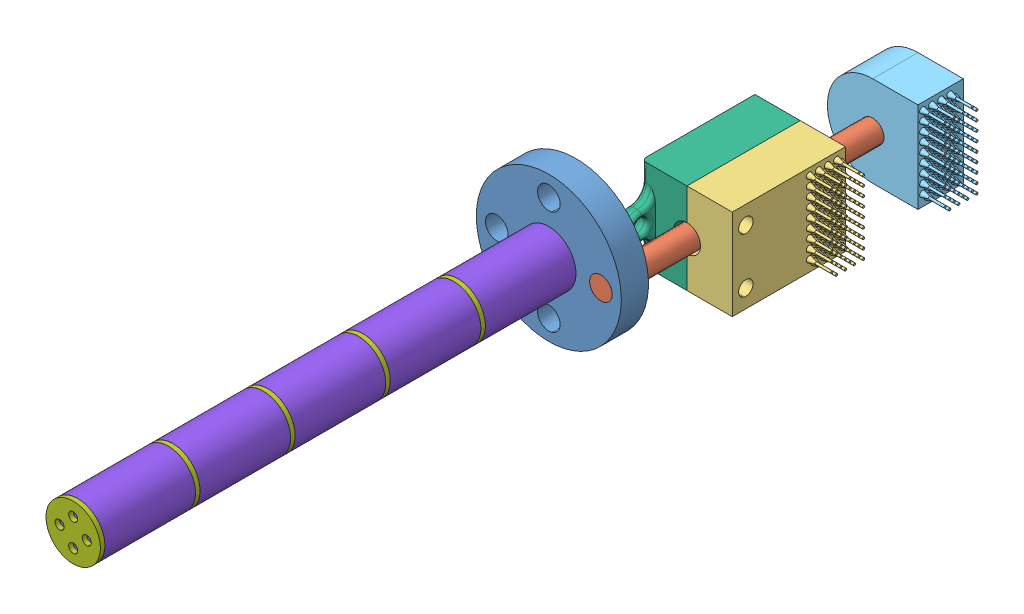
SolidWorks assembly snake, configuration ﾃﾞﾌｫﾙﾄ. Lengths in mm.
Overall size (48.52 35.13 175).
22 component instances, 8 part files, 14 mates.
Components (placement in the parent):
- plate_first-1: plate_first [ﾃﾞﾌｫﾙﾄ] at (-0.7263 1.8158 36) size (32 32 6)
- muscle_unit-1: muscle_unit [ﾃﾞﾌｫﾙﾄ] at (10.8937 1.4809 -53) x (-0.948329 -0.31729 0) z (0 0 1) size (30.19 26.94 70) (flexible)
  - axis-1: axis [ﾃﾞﾌｫﾙﾄ] at (0.0076 -0.3556 25) size (5 5 70)
  - kenzan_up-1: kenzan_up [ﾃﾞﾌｫﾙﾄ] at (0.0076 -0.3556 51) x (0.948329 -0.31729 0) z (0 0 1) size (15 20 25)
  - linear_bush-1: linear_bush [ﾃﾞﾌｫﾙﾄ] at (0.0076 -0.3556 53.25) x (0.529345 -0.848407 0) z (0 0 1) size (10 10 17)
  - kenzan_down-1: kenzan_down [ﾃﾞﾌｫﾙﾄ] at (0.0076 -0.3556 35) x (0.948329 -0.31729 0) z (0 0 -1) size (25 20 10)
  - kenzan_up_other-1: kenzan_up_other [ﾃﾞﾌｫﾙﾄ] at (0.0076 -0.3556 51) x (-0.948329 0.31729 0) z (0 0 1) size (10.14 20 31)
- snake_unit-1: snake_unit [ﾃﾞﾌｫﾙﾄ] at (3.1776 1.3921 42.5) size (12 12 21)
  - plate-1: plate [ﾃﾞﾌｫﾙﾄ] at (-3.9039 0.4237 19.5) size (12 12 1)
  - sponge-1: sponge [ﾃﾞﾌｫﾙﾄ] at (-3.9039 0.4237 -0.5) size (12 12 20)
- snake_unit-2: snake_unit [ﾃﾞﾌｫﾙﾄ] at (3.1776 1.3921 84.5) size (12 12 21)
  - plate-1: plate [ﾃﾞﾌｫﾙﾄ] at (-3.9039 0.4237 19.5) size (12 12 1)
  - sponge-1: sponge [ﾃﾞﾌｫﾙﾄ] at (-3.9039 0.4237 -0.5) size (12 12 20)
- snake_unit-3: snake_unit [ﾃﾞﾌｫﾙﾄ] at (-0.3026 5.7196 63.5) x (0 1 0) z (0 0 1) size (12 12 21)
  - plate-1: plate [ﾃﾞﾌｫﾙﾄ] at (-3.9039 0.4237 19.5) size (12 12 1)
  - sponge-1: sponge [ﾃﾞﾌｫﾙﾄ] at (-3.9039 0.4237 -0.5) size (12 12 20)
- snake_unit-4: snake_unit [ﾃﾞﾌｫﾙﾄ] at (3.1776 1.3921 105.5) size (12 12 21)
  - plate-1: plate [ﾃﾞﾌｫﾙﾄ] at (-3.9039 0.4237 19.5) size (12 12 1)
  - sponge-1: sponge [ﾃﾞﾌｫﾙﾄ] at (-3.9039 0.4237 -0.5) size (12 12 20)
- snake_unit-5: snake_unit [ﾃﾞﾌｫﾙﾄ] at (3.1776 1.3921 126.5) size (12 12 21)
  - plate-1: plate [ﾃﾞﾌｫﾙﾄ] at (-3.9039 0.4237 19.5) size (12 12 1)
  - sponge-1: sponge [ﾃﾞﾌｫﾙﾄ] at (-3.9039 0.4237 -0.5) size (12 12 20)
Mates (geometry in assembly coordinates):
- 一致1: coincident: plane of plate_first-1 through (-0.7263 1.8158 42) normal (0 0 1); plane of muscle_unit-1/axis-1 through (10.7737 1.8158 42) normal (0 0 1)
- 同心円3: concentric: circle of plate_first-1; circle of snake_unit-1/sponge-1
- 一致3: coincident: plane of plate_first-1 through (-0.7263 1.8158 42) normal (0 0 1); plane of snake_unit-1/sponge-1 through (-0.7263 1.8158 42) normal (0 0 -1)
- 同心円4: concentric: cylinder of snake_unit-1/sponge-1 through (-0.7263 1.8158 62) axis (0 0 -1) radius 6; cylinder of snake_unit-3/sponge-1 through (-0.7263 1.8158 83) axis (0 0 -1) radius 6
- 一致4: coincident: circle of snake_unit-1/plate-1; circle of snake_unit-3/sponge-1
- 一致5: coincident: circle of snake_unit-2/sponge-1; circle of snake_unit-3/plate-1
- 同心円5: concentric: cylinder of snake_unit-2/sponge-1 through (-0.7263 1.8158 104) axis (0 0 -1) radius 6; cylinder of snake_unit-3/sponge-1 through (-0.7263 1.8158 83) axis (0 0 -1) radius 6
- 一致6: coincident: circle of snake_unit-2/plate-1; circle of snake_unit-4/sponge-1
- 同心円6: concentric: cylinder of snake_unit-2/sponge-1 through (-0.7263 1.8158 104) axis (0 0 -1) radius 6; cylinder of snake_unit-4/sponge-1 through (-0.7263 1.8158 125) axis (0 0 -1) radius 6
- 同心円7: concentric: cylinder of snake_unit-4/sponge-1 through (-0.7263 1.8158 125) axis (0 0 -1) radius 6; cylinder of snake_unit-5/sponge-1 through (-0.7263 1.8158 146) axis (0 0 -1) radius 6
- 一致7: coincident: circle of snake_unit-4/plate-1; circle of snake_unit-5/sponge-1
- 一致9: coincident: plane of plate_first-1 through (-0.7263 1.8158 36) normal (0 1 0); plane of muscle_unit-1/kenzan_up-1 through (10.7737 1.8158 -2) normal (0 -1 0)
- 同心円8: concentric: cylinder of plate_first-1 through (10.7737 1.8158 36) axis (0 0 1) radius 2.5; cylinder of muscle_unit-1/axis-1 through (10.7737 1.8158 42) axis (0 0 -1) radius 2.5
- 同心円9: concentric: cylinder of plate_first-1 through (-0.7263 1.8158 42) axis (0 0 -1) radius 16; cylinder of snake_unit-1/sponge-1 through (-0.7263 1.8158 62) axis (0 0 -1) radius 6
